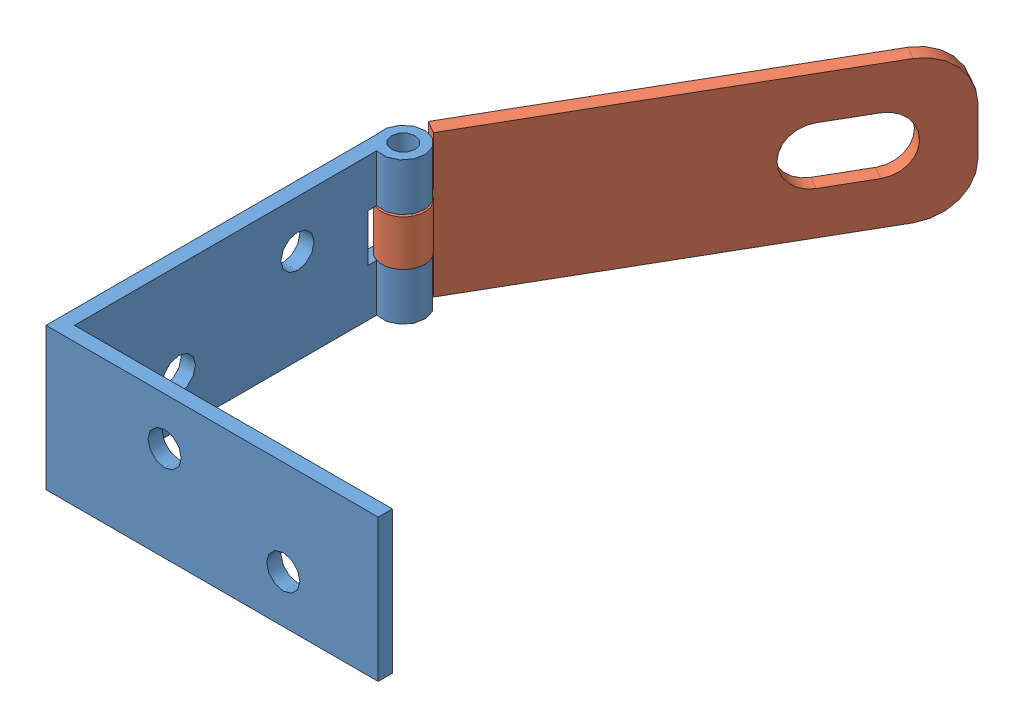
SolidWorks assembly СБСкобаК, configuration По умолчанию. Lengths in mm.
Overall size (71.85 30 150.33).
2 component instances, 2 part files, 3 mates.
Components (placement in the parent):
- Скоба-1: Скоба [По умолчанию] at origin size (70.2 30 75.5)
- Петля-1: Петля [По умолчанию] at (47.6742 0 -148.7263) x (-0.5 0 0.866025) z (-0.866025 0 -0.5) size (93.5 30 9)
Mates (geometry in assembly coordinates):
- Концентричный1: concentric aligned: cylinder of Скоба-1 through (4.3 30 -71) axis (0 -1 0) radius 4.5; cylinder of Петля-1 through (4.3 30 -71) axis (0 -1 0) radius 4.5
- Совпадение2: coincident aligned: plane of Скоба-1 through (0 30 0) normal (0 1 0); plane of Петля-1 through (3 30 -160) normal (0 1 0)
- Угол1: planar angle = 2.617994 rad anti-aligned: plane of Петля-1 through (45.0761 30 -150.2263) normal (-0.866025 0 -0.5); plane of Скоба-1 through (0 30 0) normal (-1 0 0)
